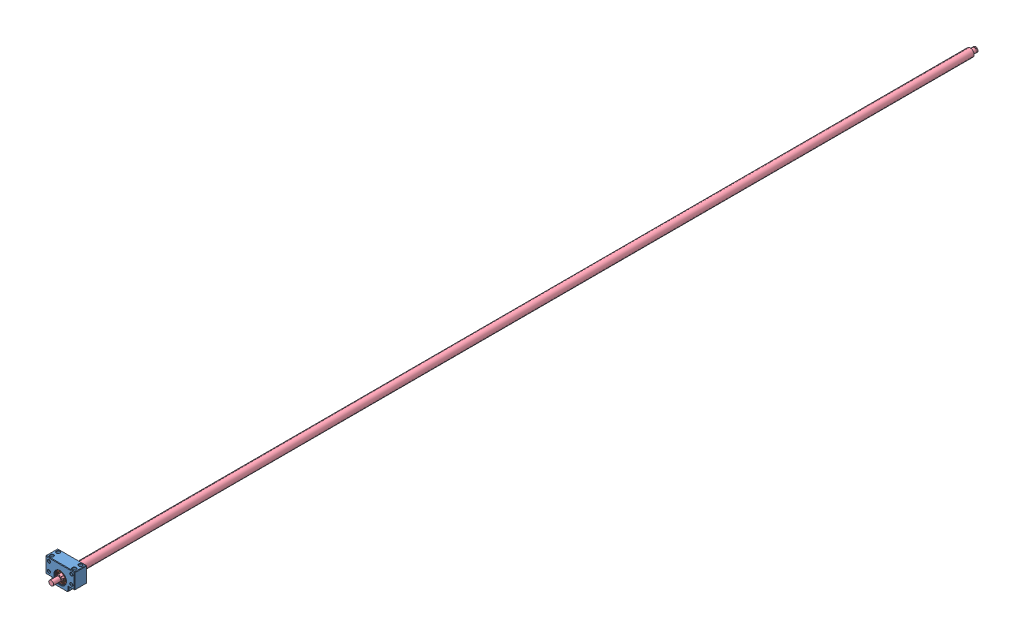
SolidWorks assembly X Screw, configuration Default. Lengths in mm.
Overall size (60 43 1900).
7 component instances, 4 part files, 4 mates.
Components (placement in the parent):
- BK12 BALLSCREW END SUPPORT-1: BK12 BALLSCREW END SUPPORT [Default] at (15.856 -21.4776 1874.1661) x (-1 0 0) z (0 0 1) size (60 43 25)
  - BK12-1-1: BK12-1 [Default] at (-11.028 26.197 -11.9785) size (60 43 25)
  - BK12-2-5: BK12-2 [Default] at (-11.028 8.197 8.0215) size (24 24 3)
  - 6001-Bearing-3: 6001-Bearing [Default] at (-11.028 8.197 0.0215) size (28 28 8)
  - 6001-Bearing-4: 6001-Bearing [Default] at (-11.028 8.197 -7.9785) size (28 28 8)
  - BK12-2-6: BK12-2 [Default] at (-11.028 8.197 -7.9785) x (-1 0 0) z (0 0 -1) size (24 24 3)
- X 1900 Ball Screw SFU16051-2: X 1900 Ball Screw SFU16051 [По умолчанию] at (31.1059 -33.8557 1815.6895) x (0 0 1) z (-0.703663 -0.710534 0) size (1900 19.01 16.42)
Mates (geometry in assembly coordinates):
- Parallel77: parallel: plane of assembly through (0 0 0) normal (0 1 0); plane of BK12 BALLSCREW END SUPPORT-1/BK12-1-1 through (56.884 -4.6746 1887.1876) normal (0 1 0); plane of assembly
- Concentric95: concentric: circle of assembly; circle of assembly; circle of X 1900 Ball Screw SFU16051-2; circle of BK12 BALLSCREW END SUPPORT-1/BK12-2-5
- Concentric155: concentric: cylinder of assembly; cylinder of assembly; cylinder of X 1900 Ball Screw SFU16051-2 through (26.884 -29.6746 1905.6876) axis (0 0 1) radius 8; cylinder of BK12 BALLSCREW END SUPPORT-1/6001-Bearing-4 through (26.884 -29.6746 1874.1876) axis (0 0 -1) radius 6
- Distance1: distance = 6.5 mm: plane of assembly; plane of assembly; plane of BK12 BALLSCREW END SUPPORT-1/BK12-1-1 through (-3.116 -4.6746 1862.1876) normal (0 0 -1); plane of X 1900 Ball Screw SFU16051-2 through (21.1997 -24.0453 1855.6876) normal (0 0 1)
